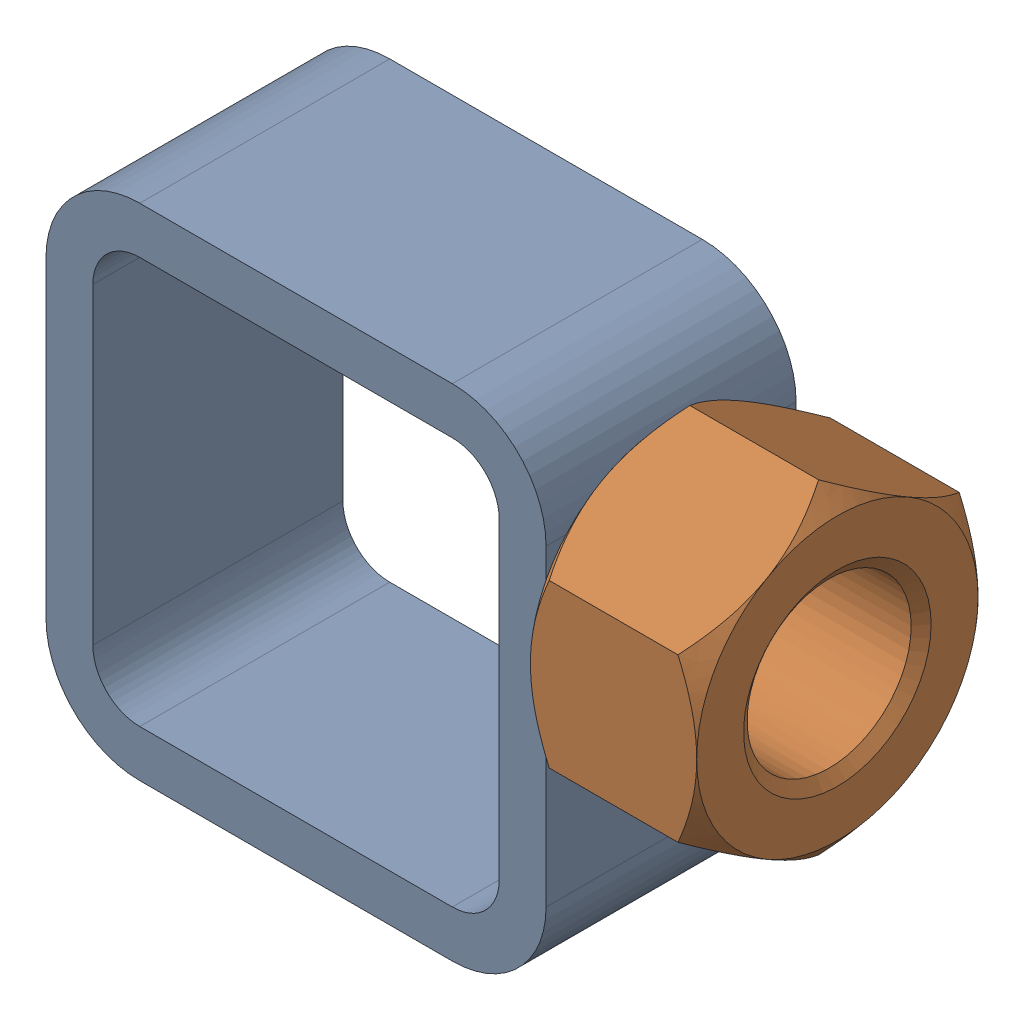
SolidWorks assembly 01-005-00-0-10, configuration Default. Lengths in mm.
Overall size (67.69 50.8 28.57).
2 component instances, 2 part files, 0 mates.
Components (placement in the parent):
- tube square_ai(PreviewCfg)-1: tube square_ai(PreviewCfg) [Default] at origin size (50.8 50.8 25.4)
- hex nut_ai(HNUT 0.7500-10-D-C)-1: hex nut_ai(HNUT 0.7500-10-D-C) [Default] at (67.691 31.75 0) x (0 0 -1) z (1 0 0) size (28.57 33 16.89)
